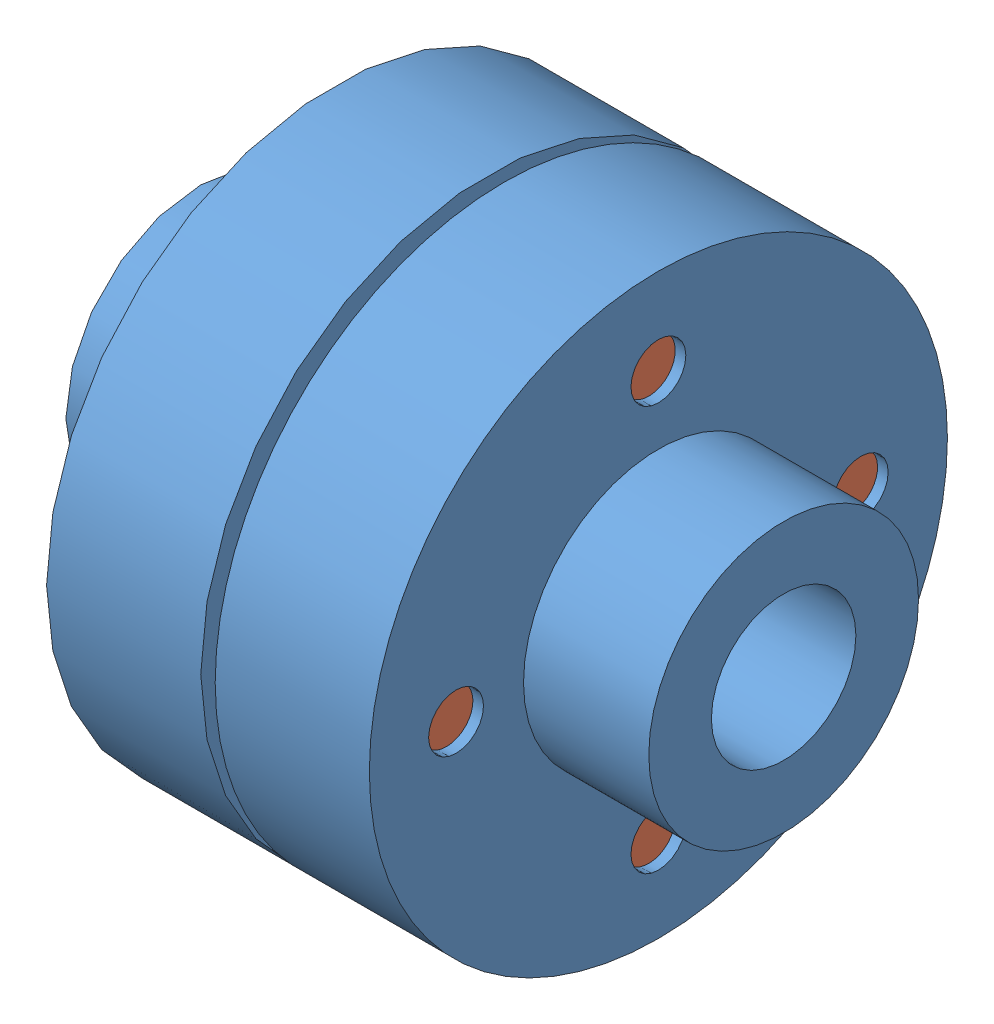
SolidWorks assembly муфта, configuration По умолчанию. Lengths in mm.
Overall size (121 121.8 121.8).
6 component instances, 2 part files, 4 mates.
Components (placement in the parent):
- Полумуфта-1: Полумуфта [Левая] at origin size (60 120 120)
- Полумуфта-2: Полумуфта [Правая] at (62 0 0) x (-1 0 0) z (0 0 -1) size (58 120 120)
- Палец-1: Палец [По умолчанию] at (31.5 42 0) x (-1 0 0) z (0 0.79976 0.60032) size (63 27 27)
- Палец-2: Палец [По умолчанию] at (31.5 0 -42) x (-1 0 0) z (0 0.60032 -0.79976) size (63 27 27)
- Палец-3: Палец [По умолчанию] at (31.5 -42 0) x (-1 0 0) z (0 -0.79976 -0.60032) size (63 27 27)
- Палец-4: Палец [По умолчанию] at (31.5 0 42) x (-1 0 0) z (0 -0.60032 0.79976) size (63 27 27)
Mates (geometry in assembly coordinates):
- Концентричный1: concentric anti-aligned: cylinder of Полумуфта-1 through (-59.7432 0 0) axis (-1 0 0) radius 15; cylinder of Полумуфта-2 through (121.7432 0 0) axis (1 0 0) radius 15
- с_: distance = 3 mm anti-aligned: plane of Полумуфта-2 through (33 -15 0) normal (-1 0 0); plane of Полумуфта-1 through (30 -15 0) normal (1 0 0)
- Совпадение2: coincident aligned: cone of Полумуфта-2 through (33 42 0) axis (1 0 0); cone of Палец-1 through (33 42 0) axis (1 0 0)
- Концентричный2: concentric aligned: cylinder of Полумуфта-1 through (-30 42 0) axis (1 0 0) radius 14; cylinder of Палец-1 through (293.4182 42 0) axis (1 0 0) radius 13.5
